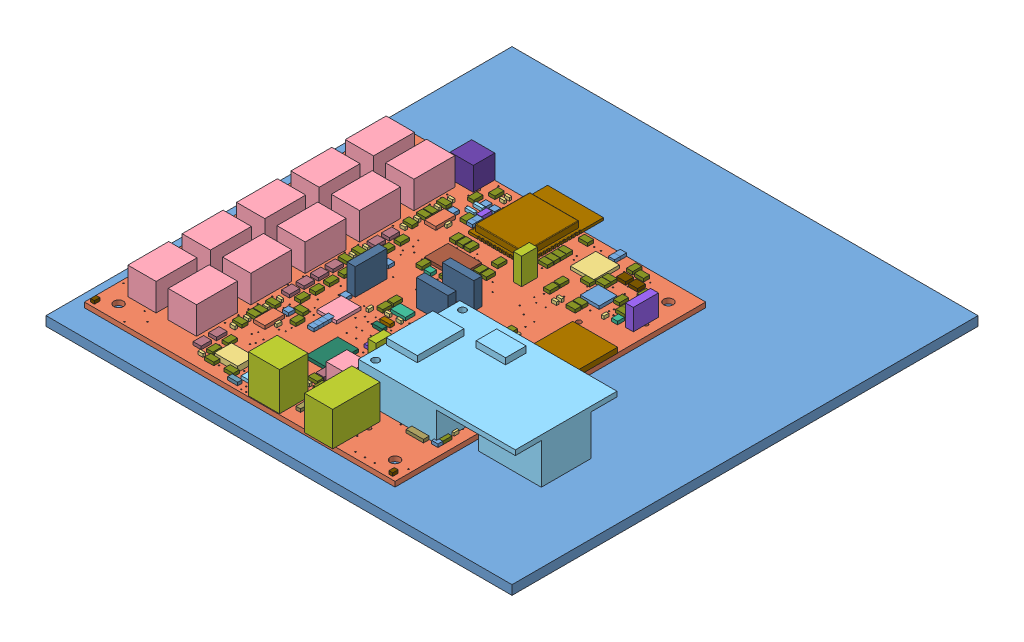
SolidWorks assembly BOX_top_all, configuration Default. Lengths in mm.
Overall size (150 19.6 150).
215 component instances, 45 part files, 1 mates.
Components (placement in the parent):
- BOX_bottom-1: BOX_bottom [Default] at (-32.1941 66.8299 152.4728) size (150 3 150)
- fra_sensor_v1-1: fra_sensor_v1 [Default] at (85.1597 71.8299 165.3728) x (0 0 -1) z (0 1 0) size (107.26 121.58 17.1)
  - fra_sensor_v1-1: fra_sensor_v1 [Default] at origin size (100 100 1.6)
  - C0603K_C0603K-1: C0603K_C0603K [Default] at (46.1264 13.6398 1.6) x (-1 0 0) z (0 0 1) size (1.6 0.8 1)
  - C0603K_C0603K-2: C0603K_C0603K [Default] at (75.4062 23.7998 1.6) x (0 -1 0) z (0 0 1) size (1.6 0.8 1)
  - C0603K_C0603K-3: C0603K_C0603K [Default] at (77.0065 23.7998 1.6) x (0 -1 0) z (0 0 1) size (1.6 0.8 1)
  - C0603K_C0603K-4: C0603K_C0603K [Default] at (56.6293 62.23 1.6) size (1.6 0.8 1)
  - C0603K_C0603K-5: C0603K_C0603K [Default] at (79.4956 11.8872 1.6) x (-1 0 0) z (0 0 1) size (1.6 0.8 1)
  - C0603K_C0603K-6: C0603K_C0603K [Default] at (40.9956 3.5814 1.6) size (1.6 0.8 1)
  - C0603K_C0603K-7: C0603K_C0603K [Default] at (32.0865 36.9316 1.6) size (1.6 0.8 1)
  - C0603K_C0603K-8: C0603K_C0603K [Default] at (40.9956 5.3467 1.6) size (1.6 0.8 1)
  - C0603K_C0603K-9: C0603K_C0603K [Default] at (39.751 14.732 1.6) size (1.6 0.8 1)
  - C0603K_C0603K-10: C0603K_C0603K [Default] at (39.751 16.3386 1.6) size (1.6 0.8 1)
  - C0603K_C0603K-11: C0603K_C0603K [Default] at (39.751 17.9451 1.6) size (1.6 0.8 1)
  - C0603K_C0603K-12: C0603K_C0603K [Default] at (28.5877 13.0175 1.6) x (-1 0 0) z (0 0 1) size (1.6 0.8 1)
  - C0603K_C0603K-13: C0603K_C0603K [Default] at (22.9426 5.4229 1.6) size (1.6 0.8 1)
  - C0603K_C0603K-14: C0603K_C0603K [Default] at (22.8981 3.4734 1.6) size (1.6 0.8 1)
  - C0603K_C0603K-15: C0603K_C0603K [Default] at (65.913 44.7357 1.6) size (1.6 0.8 1)
  - C0603K_C0603K-16: C0603K_C0603K [Default] at (21.9265 18.1292 1.6) size (1.6 0.8 1)
  - C0603K_C0603K-17: C0603K_C0603K [Default] at (60.0519 69.3864 1.6) x (0 1 0) z (0 0 1) size (1.6 0.8 1)
  - C0603K_C0603K-18: C0603K_C0603K [Default] at (55.6959 69.3864 1.6) x (0 1 0) z (0 0 1) size (1.6 0.8 1)
  - C0603K_C0603K-19: C0603K_C0603K [Default] at (4.045 66.275 1.6) x (0 1 0) z (0 0 1) size (1.6 0.8 1)
  - C0603K_C0603K-20: C0603K_C0603K [Default] at (21.1582 68.7642 1.6) x (0 1 0) z (0 0 1) size (1.6 0.8 1)
  - C0603K_C0603K-21: C0603K_C0603K [Default] at (12.1349 56.6293 1.6) x (-1 0 0) z (0 0 1) size (1.6 0.8 1)
  - C0603K_C0603K-22: C0603K_C0603K [Default] at (58.8391 42.3672 1.6) x (0 -1 0) z (0 0 1) size (1.6 0.8 1)
  - C0603K_C0603K-23: C0603K_C0603K [Default] at (96.8565 60.4901 1.6) x (0 1 0) z (0 0 1) size (1.6 0.8 1)
  - C0603K_C0603K-24: C0603K_C0603K [Default] at (95.2437 60.4901 1.6) x (0 1 0) z (0 0 1) size (1.6 0.8 1)
  - C0603K_C0603K-25: C0603K_C0603K [Default] at (22.0091 14.3129 1.6) size (1.6 0.8 1)
  - C0603K_C0603K-26: C0603K_C0603K [Default] at (21.952 16.3386 1.6) size (1.6 0.8 1)
  - C0603K_C0603K-27: C0603K_C0603K [Default] at (12.9032 40.8305 1.6) x (0 -1 0) z (0 0 1) size (1.6 0.8 1)
  - C0603K_C0603K-28: C0603K_C0603K [Default] at (55.626 42.3672 1.6) x (0 -1 0) z (0 0 1) size (1.6 0.8 1)
  - C0603K_C0603K-29: C0603K_C0603K [Default] at (43.561 51.6509 1.6) x (-1 0 0) z (0 0 1) size (1.6 0.8 1)
  - C0603K_C0603K-30: C0603K_C0603K [Default] at (11.2395 49.9173 1.6) x (0 -1 0) z (0 0 1) size (1.6 0.8 1)
  - C0603K_C0603K-31: C0603K_C0603K [Default] at (59.8043 20.3899 1.6) x (-1 0 0) z (0 0 1) size (1.6 0.8 1)
  - C0603K_C0603K-32: C0603K_C0603K [Default] at (25.2616 21.7501 1.6) x (-1 0 0) z (0 0 1) size (1.6 0.8 1)
  - C0603K_C0603K-33: C0603K_C0603K [Default] at (24.7142 25.673 1.6) x (0 1 0) z (0 0 1) size (1.6 0.8 1)
  - C0603K_C0603K-34: C0603K_C0603K [Default] at (10.2299 52.451 1.6) size (1.6 0.8 1)
  - C0603K_C0603K-35: C0603K_C0603K [Default] at (45.1167 47.2948 1.6) x (0 -1 0) z (0 0 1) size (1.6 0.8 1)
  - C0603K_C0603K-36: C0603K_C0603K [Default] at (45.1167 43.561 1.6) x (0 1 0) z (0 0 1) size (1.6 0.8 1)
  - C0603K_C0603K-37: C0603K_C0603K [Default] at (79.6544 62.5412 1.6) size (1.6 0.8 1)
  - C0603K_C0603K-38: C0603K_C0603K [Default] at (24.5809 62.23 1.6) size (1.6 0.8 1)
  - C0603K_C0603K-39: C0603K_C0603K [Default] at (16.8021 68.7642 1.6) x (0 1 0) z (0 0 1) size (1.6 0.8 1)
  - C0603K_C0603K-40: C0603K_C0603K [Default] at (27.3812 68.7642 1.6) x (0 1 0) z (0 0 1) size (1.6 0.8 1)
  - C0603K_C0603K-41: C0603K_C0603K [Default] at (31.7373 68.7642 1.6) x (0 1 0) z (0 0 1) size (1.6 0.8 1)
  - C0603K_C0603K-42: C0603K_C0603K [Default] at (76.2318 69.0753 1.6) x (0 1 0) z (0 0 1) size (1.6 0.8 1)
  - C0603K_C0603K-43: C0603K_C0603K [Default] at (71.8756 69.0753 1.6) x (0 1 0) z (0 0 1) size (1.6 0.8 1)
  - C0603K_C0603K-44: C0603K_C0603K [Default] at (82.7659 69.0753 1.6) x (0 1 0) z (0 0 1) size (1.6 0.8 1)
  - C0603K_C0603K-45: C0603K_C0603K [Default] at (87.122 69.0753 1.6) x (0 1 0) z (0 0 1) size (1.6 0.8 1)
  - 153CLV0605_153CLV0605-1: 153CLV0605_153CLV0605 [Default] at (17.6847 33.1724 1.6) size (6.7 6.7 8)
  - C0402_C0402-1: C0402_C0402 [Default] at (87.0521 62.5475 1.6) x (0 1 0) z (0 0 1) size (2.95 0.97 1)
  - C0402_C0402-2: C0402_C0402 [Default] at (89.5921 62.5475 1.6) x (0 1 0) z (0 0 1) size (2.95 0.97 1)
  - SOT323R_PESD1CANSC70-1: SOT323R_PESD1CANSC70 [Default] at (80.5355 8.7969 1.6) x (0 -1 0) z (0 0 1) size (1.92 2.2 1)
  - SOT323R_PESD1CANSC70-2: SOT323R_PESD1CANSC70 [Default] at (88.0358 10.2531 1.6) x (0 1 0) z (0 0 1) size (1.92 2.2 1)
  - SOT323R_PESD1CANSC70-3: SOT323R_PESD1CANSC70 [Default] at (15.9449 47.9235 1.6) x (-1 0 0) z (0 0 1) size (1.92 2.2 1)
  - SOT323R_PESD1CANSC70-4: SOT323R_PESD1CANSC70 [Default] at (63.6651 52.3811 1.6) size (1.92 2.2 1)
  - 1X02_1X02-1: 1X02_1X02 [Default] at (29.4386 34.3598 1.6) x (-1 0 0) z (0 0 1) size (5.08 2.62 8.5)
  - 1X02_1X02-2: 1X02_1X02 [Default] at (77.1652 35.16 1.6) size (5.08 2.62 8.5)
  - 0603_FB1_0603-1: 0603_FB1_0603 [Default] at (33.9514 41.5231 1.6) size (3.2 1.48 1)
  - 0603_FB2_0603-1: 0603_FB2_0603 [Default] at (42.6657 45.1528 1.6) x (0 1 0) z (0 0 1) size (3.2 1.48 1)
  - 0603_FB3_0603-1: 0603_FB3_0603 [Default] at (11.8237 43.8721 1.6) size (3.2 1.48 1)
  - 0603_FB4_0603-1: 0603_FB4_0603 [Default] at (11.8237 46.6725 1.6) size (3.2 1.48 1)
  - 0603_FB5_0603-1: 0603_FB5_0603 [Default] at (5.6007 35.16 1.6) size (3.2 1.48 1)
  - 0603_FB6_0603-1: 0603_FB6_0603 [Default] at (5.6007 30.1816 1.6) size (3.2 1.48 1)
  - 0603_FB7_0603-1: 0603_FB7_0603 [Default] at (2.0447 53.5559 1.6) x (0 1 0) z (0 0 1) size (3.2 1.48 1)
  - 0603_FB8_0603-1: 0603_FB8_0603 [Default] at (40.1384 45.1167 1.6) x (0 1 0) z (0 0 1) size (3.2 1.48 1)
  - 0603_FB9_0603-1: 0603_FB9_0603 [Default] at (33.9153 39.2049 1.6) size (3.2 1.48 1)
  - 0603_FB10_0603-1: 0603_FB10_0603 [Default] at (14.9352 50.8419 1.6) x (-1 0 0) z (0 0 1) size (3.2 1.48 1)
  - FIDUCIAL_1MM_FIDUCIAL__-1: FIDUCIAL_1MM_FIDUCIAL__ [Default] at (2 98 1.6) size (1.75 1.25 1)
  - FIDUCIAL_1MM_FIDUCIAL__-2: FIDUCIAL_1MM_FIDUCIAL__ [Default] at (98 98 1.6) size (1.75 1.25 1)
  - FIDUCIAL_1MM_FIDUCIAL__-3: FIDUCIAL_1MM_FIDUCIAL__ [Default] at (2 2 1.6) size (1.75 1.25 1)
  - MLP28_CP2101-1: MLP28_CP2101 [Default] at (83.82 18.0975 1.6) x (0 1 0) z (0 0 1) size (6.1 5.78 1)
  - SOP50P490X11010N_1100000_ADS1115IDGSR_1100000-1: SOP50P490X11010N_1100000_ADS1115IDGSR_1100000 [Default] at (56.6293 65.0303 1.6) x (-1 0 0) z (0 0 1) size (6.35 3.62 1.1)
  - SOP50P490X11010N_1100000_ADS1115IDGSR_1100000-2: SOP50P490X11010N_1100000_ADS1115IDGSR_1100000 [Default] at (79.6989 65.2399 1.6) x (-1 0 0) z (0 0 1) size (6.35 3.62 1.1)
  - SOP50P490X11010N_1100000_ADS1115IDGSR_1100000-3: SOP50P490X11010N_1100000_ADS1115IDGSR_1100000 [Default] at (24.5364 65.0875 1.6) x (-1 0 0) z (0 0 1) size (6.35 3.62 1.1)
  - SOIC127P600X1758N_1750000_P82B715DR_1750000-1: SOIC127P600X1758N_1750000_P82B715DR_1750000 [Default] at (7.7788 59.4297 1.6) x (0 1 0) z (0 0 1) size (7.5 5.53 1.75)
  - TSSOP24_PCA9555PW-1: TSSOP24_PCA9555PW [Default] at (38.2715 56.3181 1.6) x (-1 0 0) z (0 0 1) size (7.78 6.24 1)
  - STSOT89_LDK320ADU50R-1: STSOT89_LDK320ADU50R [Default] at (6.1468 50.8889 1.6) x (0 1 0) z (0 0 1) size (4.7 5.09 1)
  - 2X6_ETH_CONN-1: 2X6_ETH_CONN [Default] at (27.305 26.67 0) x (1 0 0) z (0 0 -1) size (15.34 5.46 1)
  - PJ059A_11000000_PJ059A_11000000-1: PJ059A_11000000_PJ059A_11000000 [Default] at (10.5791 23.6474 1.6) size (15.25 9.05 11)
  - USBBMICROSMD_VERT_WM9734TRND-1: USBBMICROSMD_VERT_WM9734TRND [Default] at (84.1285 5.2407 1.6) size (8.1 2.55 6.8)
  - 1140084168_1680000_1140084168_1680000-1: 1140084168_1680000_1140084168_1680000 [Default] at (64.0771 7.1336 1.6) size (14.95 14.45 1.68)
  - 1X04_1X04-1: 1X04_1X04 [Default] at (50 59 1.6) size (10.16 2.62 8.5)
  - 1X04_1X04-2: 1X04_1X04 [Default] at (61.3791 39.8272 1.6) x (0 -1 0) z (0 0 1) size (10.16 2.62 8.5)
  - 1X04_1X04-3: 1X04_1X04 [Default] at (53.086 39.8272 1.6) x (0 -1 0) z (0 0 1) size (10.16 2.62 8.5)
  - 2X05_1_27MM_SMT_DNI-1: 2X05_1_27MM_SMT_DNI [Default] at (70.2922 51.4515 1.6) x (0 -1 0) z (0 0 1) size (10.74 7.6 1)
  - SRP5030CA_SRP5030CA1R5M-1: SRP5030CA_SRP5030CA1R5M [Default] at (36.1696 9.1821 1.6) x (-1 0 0) z (0 0 1) size (5.47 5.58 1)
  - SRP5030CA_SRP5030CA1R5M-2: SRP5030CA_SRP5030CA1R5M [Default] at (18.0086 8.9726 1.6) x (-1 0 0) z (0 0 1) size (5.47 5.58 1)
  - SOT23WIDE_FDN306P-1: SOT23WIDE_FDN306P [Default] at (18.2816 40.786 1.6) size (3.35 2.59 1)
  - SOT23WIDE_FDN306P-2: SOT23WIDE_FDN306P [Default] at (7.1564 69.1868 1.6) size (3.35 2.59 1)
  - SOT23WIDE_FDN306P-3: SOT23WIDE_FDN306P [Default] at (12.1349 69.1868 1.6) size (3.35 2.59 1)
  - SOT23WIDE_FDN306P-4: SOT23WIDE_FDN306P [Default] at (40.4806 69.3735 1.6) size (3.35 2.59 1)
  - SOT23WIDE_FDN306P-5: SOT23WIDE_FDN306P [Default] at (35.7823 69.3864 1.6) size (3.35 2.59 1)
  - SOT23WIDE_FDN306P-6: SOT23WIDE_FDN306P [Default] at (63.1634 69.1868 1.6) size (3.35 2.59 1)
  - SOT23WIDE_FDN306P-7: SOT23WIDE_FDN306P [Default] at (67.7062 69.1686 1.6) size (3.35 2.59 1)
  - SOT23WIDE_FDN306P-8: SOT23WIDE_FDN306P [Default] at (94.9008 87.122 1.6) x (0 1 0) z (0 0 1) size (3.35 2.59 1)
  - SOT23WIDE_FDN306P-9: SOT23WIDE_FDN306P [Default] at (94.9008 81.2101 1.6) x (0 1 0) z (0 0 1) size (3.35 2.59 1)
  - SOT23WIDE_FDN306P-10: SOT23WIDE_FDN306P [Default] at (45.1167 69.3864 1.6) size (3.35 2.59 1)
  - SOT23WIDE_FDN306P-11: SOT23WIDE_FDN306P [Default] at (49.784 69.3864 1.6) size (3.35 2.59 1)
  - SOT23_SI2300DS-1: SOT23_SI2300DS [Default] at (35.0393 34.3345 1.6) x (0 1 0) z (0 0 1) size (2.92 2.59 1)
  - TO252_DNI-1: TO252_DNI [Default] at (24.892 45.1167 1.6) x (0 1 0) z (0 0 1) size (6.66 10.26 1)
  - R0603_R0603-1: R0603_R0603 [Default] at (97.1804 20.212 1.6) x (-1 0 0) z (0 0 1) size (2.95 1.97 1)
  - R0603_R0603-2: R0603_R0603 [Default] at (96.5454 17.0371 1.6) x (0 -1 0) z (0 0 1) size (2.95 1.97 1)
  - R0603_R0603-3: R0603_R0603 [Default] at (76.8477 19.3675 1.6) x (0 -1 0) z (0 0 1) size (2.95 1.97 1)
  - R0603_R0603-4: R0603_R0603 [Default] at (79.0639 19.3675 1.6) x (0 -1 0) z (0 0 1) size (2.95 1.97 1)
  - R0603_R0603-5: R0603_R0603 [Default] at (85.081 10.0032 1.6) x (0 1 0) z (0 0 1) size (2.95 1.97 1)
  - R0603_R0603-6: R0603_R0603 [Default] at (83.4935 10.0032 1.6) x (0 1 0) z (0 0 1) size (2.95 1.97 1)
  - R0603_R0603-7: R0603_R0603 [Default] at (86.4616 24.2945 1.6) x (0 1 0) z (0 0 1) size (2.95 1.97 1)
  - R0603_R0603-8: R0603_R0603 [Default] at (64.5668 55.4291 1.6) x (-1 0 0) z (0 0 1) size (2.95 1.97 1)
  - R0603_R0603-9: R0603_R0603 [Default] at (84.4804 61.068 1.6) size (2.95 1.97 1)
  - R0603_R0603-10: R0603_R0603 [Default] at (77.1652 57.1627 1.6) size (2.95 1.97 1)
  - R0603_R0603-11: R0603_R0603 [Default] at (28.5305 11.1252 1.6) x (-1 0 0) z (0 0 1) size (2.95 1.97 1)
  - R0603_R0603-12: R0603_R0603 [Default] at (77.2414 43.688 1.6) size (2.95 1.97 1)
  - R0603_R0603-13: R0603_R0603 [Default] at (77.216 52.6034 1.6) size (2.95 1.97 1)
  - R0603_R0603-14: R0603_R0603 [Default] at (91.4781 65.6527 1.6) size (2.95 1.97 1)
  - R0603_R0603-15: R0603_R0603 [Default] at (57.8739 69.3864 1.6) x (0 1 0) z (0 0 1) size (2.95 1.97 1)
  - R0603_R0603-16: R0603_R0603 [Default] at (46.1264 11.8745 1.6) x (-1 0 0) z (0 0 1) size (2.95 1.97 1)
  - R0603_R0603-17: R0603_R0603 [Default] at (88.9254 36.2331 1.6) x (0 -1 0) z (0 0 1) size (2.95 1.97 1)
  - R0603_R0603-18: R0603_R0603 [Default] at (53.5178 69.3864 1.6) x (0 1 0) z (0 0 1) size (2.95 1.97 1)
  - R0603_R0603-19: R0603_R0603 [Default] at (78.4924 28.2004 1.6) size (2.95 1.97 1)
  - R0603_R0603-20: R0603_R0603 [Default] at (42.8561 36.7792 1.6) x (-1 0 0) z (0 0 1) size (2.95 1.97 1)
  - R0603_R0603-21: R0603_R0603 [Default] at (38.5889 34.309 1.6) x (0 1 0) z (0 0 1) size (2.95 1.97 1)
  - R0603_R0603-22: R0603_R0603 [Default] at (37.7628 3.5808 1.6) size (2.95 1.97 1)
  - R0603_R0603-23: R0603_R0603 [Default] at (81.8174 28.2665 1.6) size (2.95 1.97 1)
  - R0603_R0603-24: R0603_R0603 [Default] at (77.2287 54.8703 1.6) size (2.95 1.97 1)
  - R0603_R0603-25: R0603_R0603 [Default] at (64.8398 48.1647 1.6) x (0 1 0) z (0 0 1) size (2.95 1.97 1)
  - R0603_R0603-26: R0603_R0603 [Default] at (55.8355 46.1709 1.6) x (-1 0 0) z (0 0 1) size (2.95 1.97 1)
  - R0603_R0603-27: R0603_R0603 [Default] at (59.2899 46.1328 1.6) size (2.95 1.97 1)
  - R0603_R0603-28: R0603_R0603 [Default] at (46.5963 8.8836 1.6) size (2.95 1.97 1)
  - R0603_R0603-29: R0603_R0603 [Default] at (46.5963 6.7627 1.6) size (2.95 1.97 1)
  - R0603_R0603-30: R0603_R0603 [Default] at (46.5963 4.6387 1.6) size (2.95 1.97 1)
  - R0603_R0603-31: R0603_R0603 [Default] at (90.9892 36.2585 1.6) x (0 -1 0) z (0 0 1) size (2.95 1.97 1)
  - R0603_R0603-32: R0603_R0603 [Default] at (72.1106 42.1894 1.6) x (-1 0 0) z (0 0 1) size (2.95 1.97 1)
  - R0603_R0603-33: R0603_R0603 [Default] at (4.045 56.6293 1.6) x (0 1 0) z (0 0 1) size (2.95 1.97 1)
  - R0603_R0603-34: R0603_R0603 [Default] at (4.045 62.8523 1.6) x (0 -1 0) z (0 0 1) size (2.95 1.97 1)
  - R0603_R0603-35: R0603_R0603 [Default] at (32.0485 62.23 1.6) x (0 1 0) z (0 0 1) size (2.95 1.97 1)
  - R0603_R0603-36: R0603_R0603 [Default] at (28.6258 60.0519 1.6) size (2.95 1.97 1)
  - R0603_R0603-37: R0603_R0603 [Default] at (42.9387 24.5809 1.6) x (0 1 0) z (0 0 1) size (2.95 1.97 1)
  - R0603_R0603-38: R0603_R0603 [Default] at (88.265 21.2725 1.6) x (0 -1 0) z (0 0 1) size (2.95 1.97 1)
  - R0603_R0603-39: R0603_R0603 [Default] at (86.36 13.6525 1.6) size (2.95 1.97 1)
  - R0603_R0603-40: R0603_R0603 [Default] at (91.7512 11.4363 1.6) x (-1 0 0) z (0 0 1) size (2.95 1.97 1)
  - R0603_R0603-41: R0603_R0603 [Default] at (90.3256 21.2852 1.6) x (0 -1 0) z (0 0 1) size (2.95 1.97 1)
  - R0603_R0603-42: R0603_R0603 [Default] at (72.1106 44.4691 1.6) x (-1 0 0) z (0 0 1) size (2.95 1.97 1)
  - R0603_R0603-43: R0603_R0603 [Default] at (97.4154 35.9474 1.6) x (0 -1 0) z (0 0 1) size (2.95 1.97 1)
  - R0603_R0603-44: R0603_R0603 [Default] at (19.3675 3.4925 1.6) size (2.95 1.97 1)
  - R0603_R0603-45: R0603_R0603 [Default] at (28.3464 8.2486 1.6) size (2.95 1.97 1)
  - R0603_R0603-46: R0603_R0603 [Default] at (28.3407 4.0488 1.6) size (2.95 1.97 1)
  - R0603_R0603-47: R0603_R0603 [Default] at (28.3477 6.1652 1.6) size (2.95 1.97 1)
  - R0603_R0603-48: R0603_R0603 [Default] at (13.9446 37.865 1.6) x (-1 0 0) z (0 0 1) size (2.95 1.97 1)
  - R0603_R0603-49: R0603_R0603 [Default] at (15.3162 40.8305 1.6) x (0 -1 0) z (0 0 1) size (2.95 1.97 1)
  - R0603_R0603-50: R0603_R0603 [Default] at (86.8489 36.2331 1.6) x (0 -1 0) z (0 0 1) size (2.95 1.97 1)
  - R0603_R0603-51: R0603_R0603 [Default] at (84.7789 36.2331 1.6) x (0 -1 0) z (0 0 1) size (2.95 1.97 1)
  - R0603_R0603-52: R0603_R0603 [Default] at (55.1752 22.4536 1.6) x (0 1 0) z (0 0 1) size (2.95 1.97 1)
  - R0603_R0603-53: R0603_R0603 [Default] at (59.817 22.8409 1.6) x (-1 0 0) z (0 0 1) size (2.95 1.97 1)
  - R0603_R0603-54: R0603_R0603 [Default] at (7.1564 65.3415 1.6) x (-1 0 0) z (0 0 1) size (2.95 1.97 1)
  - R0603_R0603-55: R0603_R0603 [Default] at (96.0692 63.4556 1.6) x (-1 0 0) z (0 0 1) size (2.95 1.97 1)
  - R0603_R0603-56: R0603_R0603 [Default] at (12.1349 65.3415 1.6) x (-1 0 0) z (0 0 1) size (2.95 1.97 1)
  - R0603_R0603-57: R0603_R0603 [Default] at (40.4495 65.5412 1.6) x (-1 0 0) z (0 0 1) size (2.95 1.97 1)
  - R0603_R0603-58: R0603_R0603 [Default] at (35.7823 65.6527 1.6) x (-1 0 0) z (0 0 1) size (2.95 1.97 1)
  - R0603_R0603-59: R0603_R0603 [Default] at (63.1634 65.6527 1.6) x (-1 0 0) z (0 0 1) size (2.95 1.97 1)
  - R0603_R0603-60: R0603_R0603 [Default] at (67.8307 65.6527 1.6) x (-1 0 0) z (0 0 1) size (2.95 1.97 1)
  - R0603_R0603-61: R0603_R0603 [Default] at (98.0122 87.122 1.6) x (0 -1 0) z (0 0 1) size (2.95 1.97 1)
  - R0603_R0603-62: R0603_R0603 [Default] at (98.1238 81.2101 1.6) x (0 -1 0) z (0 0 1) size (2.95 1.97 1)
  - R0603_R0603-63: R0603_R0603 [Default] at (45.1167 65.6527 1.6) x (-1 0 0) z (0 0 1) size (2.95 1.97 1)
  - R0603_R0603-64: R0603_R0603 [Default] at (49.784 65.6527 1.6) x (-1 0 0) z (0 0 1) size (2.95 1.97 1)
  - R0603_R0603-65: R0603_R0603 [Default] at (46.3614 49.784 1.6) size (2.95 1.97 1)
  - R0603_R0603-66: R0603_R0603 [Default] at (49.784 49.784 1.6) x (-1 0 0) z (0 0 1) size (2.95 1.97 1)
  - R0603_R0603-67: R0603_R0603 [Default] at (23.3362 68.7642 1.6) x (0 1 0) z (0 0 1) size (2.95 1.97 1)
  - R0603_R0603-68: R0603_R0603 [Default] at (18.9802 68.7642 1.6) x (0 1 0) z (0 0 1) size (2.95 1.97 1)
  - R0603_R0603-69: R0603_R0603 [Default] at (25.5143 68.7642 1.6) x (0 1 0) z (0 0 1) size (2.95 1.97 1)
  - R0603_R0603-70: R0603_R0603 [Default] at (29.5592 68.7642 1.6) x (0 1 0) z (0 0 1) size (2.95 1.97 1)
  - R0603_R0603-71: R0603_R0603 [Default] at (78.4098 69.0753 1.6) x (0 1 0) z (0 0 1) size (2.95 1.97 1)
  - R0603_R0603-72: R0603_R0603 [Default] at (74.0537 69.0753 1.6) x (0 1 0) z (0 0 1) size (2.95 1.97 1)
  - R0603_R0603-73: R0603_R0603 [Default] at (80.5879 69.0753 1.6) x (0 1 0) z (0 0 1) size (2.95 1.97 1)
  - R0603_R0603-74: R0603_R0603 [Default] at (84.944 69.0753 1.6) x (0 1 0) z (0 0 1) size (2.95 1.97 1)
  - B3F31XX_S1_B3F31XX-1: B3F31XX_S1_B3F31XX [Default] at (95.8977 71.6597 1.6) x (0 1 0) z (0 0 1) size (7.44 6.93 7.5)
  - SOT23_BC847-1: SOT23_BC847 [Default] at (93.0529 18.942 1.6) x (0 1 0) z (0 0 1) size (2.92 2.59 1)
  - SOT23_BC847-2: SOT23_BC847 [Default] at (93.0529 15.132 1.6) x (0 1 0) z (0 0 1) size (2.92 2.59 1)
  - TP10R_TPTP10R-1: TP10R_TPTP10R [Default] at (35.3758 3.6004 1.6) size (2 2 1)
  - TP10R_TPTP10R-2: TP10R_TPTP10R [Default] at (36.6141 16.4275 1.6) size (2 2 1)
  - TP10R_TPTP10R-3: TP10R_TPTP10R [Default] at (18.4595 16.6306 1.6) size (2 2 1)
  - TP10R_TPTP10R-4: TP10R_TPTP10R [Default] at (17.3228 3.5179 1.6) size (2 2 1)
  - TP10R_TPTP10R-5: TP10R_TPTP10R [Default] at (41.1544 33.3439 1.6) size (2 2 1)
  - TP10R_TPTP10R-6: TP10R_TPTP10R [Default] at (91.1669 59.1185 1.6) size (2 2 1)
  - TP10R_TPTP10R-7: TP10R_TPTP10R [Default] at (91.1669 61.9188 1.6) size (2 2 1)
  - TP10R_TPTP10R-8: TP10R_TPTP10R [Default] at (85.5662 59.1185 1.6) size (2 2 1)
  - TP10R_TPTP10R-9: TP10R_TPTP10R [Default] at (84.0105 59.1185 1.6) size (2 2 1)
  - TP10R_TPTP10R-10: TP10R_TPTP10R [Default] at (29.8704 64.0969 1.6) size (2 2 1)
  - TP10R_TPTP10R-11: TP10R_TPTP10R [Default] at (21.9012 35.56 1.6) size (2 2 1)
  - TP10R_TPTP10R-12: TP10R_TPTP10R [Default] at (84.0105 65.3415 1.6) size (2 2 1)
  - TP10R_TPTP10R-13: TP10R_TPTP10R [Default] at (43.1609 59.0677 1.6) size (2 2 1)
  - TP10R_TPTP10R-14: TP10R_TPTP10R [Default] at (29.5592 55.6959 1.6) size (2 2 1)
  - TP10R_TPTP10R-15: TP10R_TPTP10R [Default] at (31.115 55.6959 1.6) size (2 2 1)
  - TP10R_TPTP10R-16: TP10R_TPTP10R [Default] at (32.6707 55.6959 1.6) size (2 2 1)
  - TP10R_TPTP10R-17: TP10R_TPTP10R [Default] at (34.2265 55.6959 1.6) size (2 2 1)
  - TP10R_TPTP10R-18: TP10R_TPTP10R [Default] at (97.0788 26.4477 1.6) size (2 2 1)
  - TP10R_TPTP10R-19: TP10R_TPTP10R [Default] at (98.9457 26.4477 1.6) size (2 2 1)
  - TP10R_TPTP10R-20: TP10R_TPTP10R [Default] at (59.1185 61.2965 1.6) size (2 2 1)
  - SOT236_TPS563249DDCR-1: SOT236_TPS563249DDCR [Default] at (24.3586 9.9886 1.6) x (0 -1 0) z (0 0 1) size (2.97 3 1)
  - SOT236_TPS563249DDCR-2: SOT236_TPS563249DDCR [Default] at (42.2593 10.3441 1.6) x (0 -1 0) z (0 0 1) size (2.97 3 1)
  - 2X03_1_27MM_SMT_DNI-1: 2X03_1_27MM_SMT_DNI [Default] at (91.3448 26.8161 1.6) x (-1 0 0) z (0 0 1) size (8.2 7.6 1)
  - WE_61200621621_CONN_03X2_WE_61200621621-1: WE_61200621621_CONN_03X2_WE_61200621621 [Default] at (15 90 1.6) x (0 -1 0) z (0 0 1) size (9.1 13.16 8.8)
  - WE_61200621621_CONN_03X2_WE_61200621621-2: WE_61200621621_CONN_03X2_WE_61200621621 [Default] at (15 77 1.6) x (0 -1 0) z (0 0 1) size (9.1 13.16 8.8)
  - WE_61200621621_CONN_03X2_WE_61200621621-3: WE_61200621621_CONN_03X2_WE_61200621621 [Default] at (32.5 90 1.6) x (0 -1 0) z (0 0 1) size (9.1 13.16 8.8)
  - WE_61200621621_CONN_03X2_WE_61200621621-4: WE_61200621621_CONN_03X2_WE_61200621621 [Default] at (32.5 77 1.6) x (0 -1 0) z (0 0 1) size (9.1 13.16 8.8)
  - WE_61200621621_CONN_03X2_WE_61200621621-5: WE_61200621621_CONN_03X2_WE_61200621621 [Default] at (67.5 90 1.6) x (0 -1 0) z (0 0 1) size (9.1 13.16 8.8)
  - WE_61200621621_CONN_03X2_WE_61200621621-6: WE_61200621621_CONN_03X2_WE_61200621621 [Default] at (67.5 77 1.6) x (0 -1 0) z (0 0 1) size (9.1 13.16 8.8)
  - WE_61200621621_CONN_03X2_WE_61200621621-7: WE_61200621621_CONN_03X2_WE_61200621621 [Default] at (85 90 1.6) x (0 -1 0) z (0 0 1) size (9.1 13.16 8.8)
  - WE_61200621621_CONN_03X2_WE_61200621621-8: WE_61200621621_CONN_03X2_WE_61200621621 [Default] at (85 77 1.6) x (0 -1 0) z (0 0 1) size (9.1 13.16 8.8)
  - WE_61200621621_CONN_03X2_WE_61200621621-9: WE_61200621621_CONN_03X2_WE_61200621621 [Default] at (50 90 1.6) x (0 -1 0) z (0 0 1) size (9.1 13.16 8.8)
  - WE_61200621621_CONN_03X2_WE_61200621621-10: WE_61200621621_CONN_03X2_WE_61200621621 [Default] at (50 77 1.6) x (0 -1 0) z (0 0 1) size (9.1 13.16 8.8)
  - ETH_MODULE_OUTLINE_SMALL_ETH_MODULE_OUTLINE-1: ETH_MODULE_OUTLINE_SMALL_ETH_MODULE_OUTLINE [Default] at (17.145 -21.59 1.6) size (32.7 50.55 17.1)
  - SOT5051_PCA9509DP-1: SOT5051_PCA9509DP [Default] at (47.9171 45.4279 1.6) size (3.13 4.8 1)
  - W237102_W237102-1: W237102_W237102 [Default] at (5.715 42.4307 1.6) x (0 -1 0) z (0 0 1) size (9.98 9.2 12.3)
  - CRYSTALSMD3_2X1_5MM_DNI-1: CRYSTALSMD3_2X1_5MM_DNI [Default] at (88.3222 59.69 1.6) size (3.33 1.7 1)
  - esp32wroom-1: esp32wroom [Default] at (93.54 52.6943 1.6) x (0 -1 0) z (-1 0 0) size (18.01 2.81 25.51)
Mates (geometry in assembly coordinates):
- Distance1: distance = 3.6 mm aligned: plane of BOX_bottom-1 through (-32.1941 69.8299 152.4728) normal (0 1 0); plane of fra_sensor_v1-1/fra_sensor_v1-1 through (85.1597 73.4299 165.3728) normal (0 1 0)
